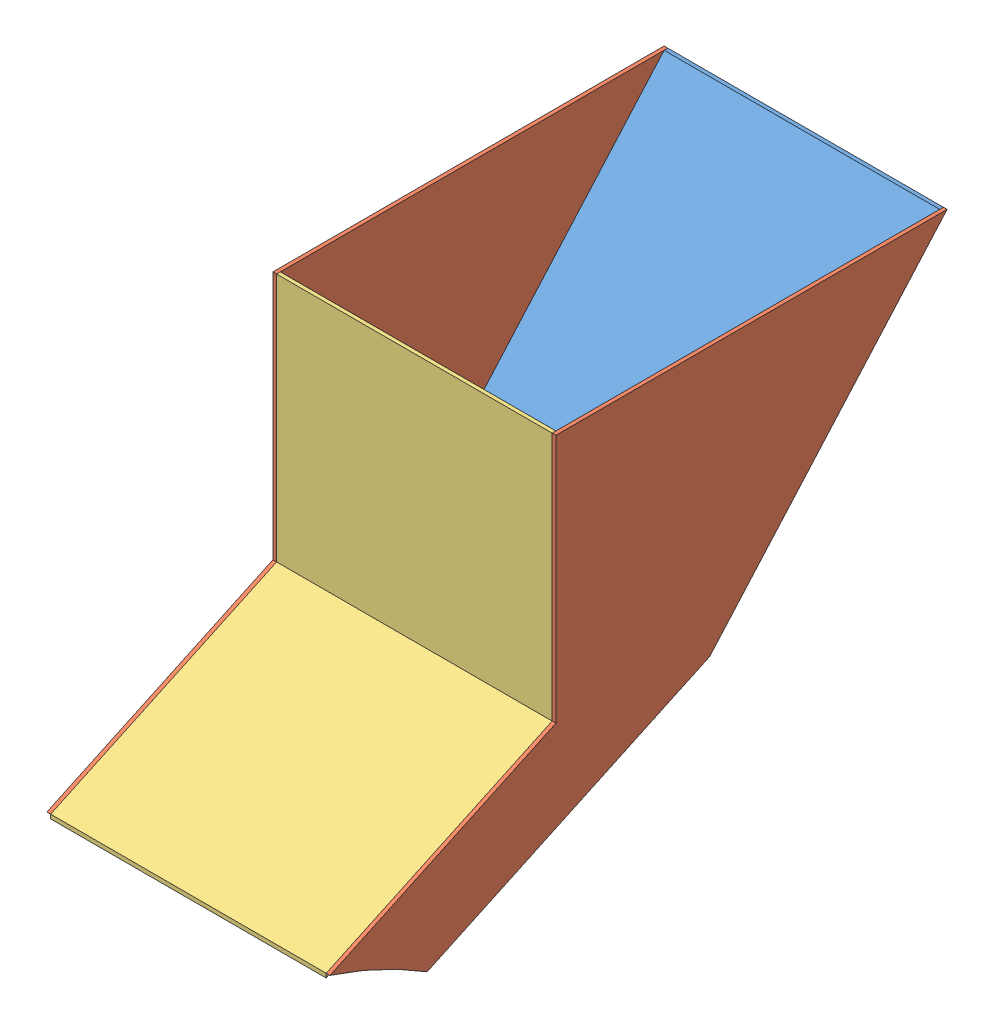
SolidWorks assembly Funnel Assembly 3.0, configuration Default. Lengths in mm.
Overall size (115.31 163.09 251.48).
4 component instances, 3 part files, 9 mates.
Components (placement in the parent):
- Funnel Assembly - Right Side 3.0-1: Funnel Assembly - Right Side 3.0 [Default] at (46.768 -22.0147 58.5118) x (1 0 0) z (0 -0.00008 1) size (112.27 163.07 211.86)
- Funnel Assembly - Side Panel 2.0-1: Funnel Assembly - Side Panel 2.0 [Default] at (45.2491 -175.4605 153.76) x (0 0.000029 -1) z (1 0 0) size (251.47 163.08 1.52)
- Funnel Assembly - Side Panel 2.0-2: Funnel Assembly - Side Panel 2.0 [Default] at (159.036 -175.4605 153.76) x (0 0.000029 -1) z (1 0 0) size (251.47 163.08 1.52)
- Funnel Assembly - Left Side 3.0-2: Funnel Assembly - Left Side 3.0 [Default] at (46.768 -4.9876 98.1339) x (1 0 0) z (0 -0.000029 1) size (112.27 146.21 93.6)
Mates (geometry in assembly coordinates):
- Coincident2: coincident anti-aligned: plane of Funnel Assembly - Right Side 3.0-1 through (46.768 -22.0147 58.5118) normal (-1 0 0); plane of Funnel Assembly - Side Panel 2.0-1 through (46.768 -175.4605 153.76) normal (1 0 0)
- Coincident3: coincident aligned: line of Funnel Assembly - Right Side 3.0-1 through (46.768 30.1482 -56.5851) axis (0 0.749125 -0.662429); line of Funnel Assembly - Side Panel 2.0-1 through (46.768 30.1482 -56.5851) axis (0 0.749125 -0.662429)
- Coincident6: coincident: point of Funnel Assembly - Right Side 3.0-1; point of Funnel Assembly - Side Panel 2.0-1
- Coincident7: coincident anti-aligned: plane of Funnel Assembly - Right Side 3.0-1 through (159.036 -22.0147 58.5118) normal (1 0 0); plane of Funnel Assembly - Side Panel 2.0-2 through (159.036 -175.4605 153.76) normal (-1 0 0)
- Coincident8: coincident aligned: line of Funnel Assembly - Right Side 3.0-1 through (159.036 30.1482 -56.5851) axis (0 0.749125 -0.662429); line of Funnel Assembly - Side Panel 2.0-2 through (159.036 30.1482 -56.5851) axis (0 0.749125 -0.662429)
- Coincident9: coincident: point of Funnel Assembly - Right Side 3.0-1; point of Funnel Assembly - Side Panel 2.0-2
- Coincident10: coincident anti-aligned: plane of Funnel Assembly - Side Panel 2.0-2 through (159.036 -175.4605 153.76) normal (-1 0 0); plane of Funnel Assembly - Left Side 3.0-2 through (159.036 -4.9876 98.1339) normal (1 0 0)
- Coincident11: coincident aligned: line of Funnel Assembly - Side Panel 2.0-2 through (159.036 139.5531 6.0572) axis (0 -1 -0.000029); line of Funnel Assembly - Left Side 3.0-2 through (159.036 139.5531 6.0572) axis (0 -1 -0.000029)
- Coincident12: coincident: point of Funnel Assembly - Side Panel 2.0-2; point of Funnel Assembly - Left Side 3.0-2
